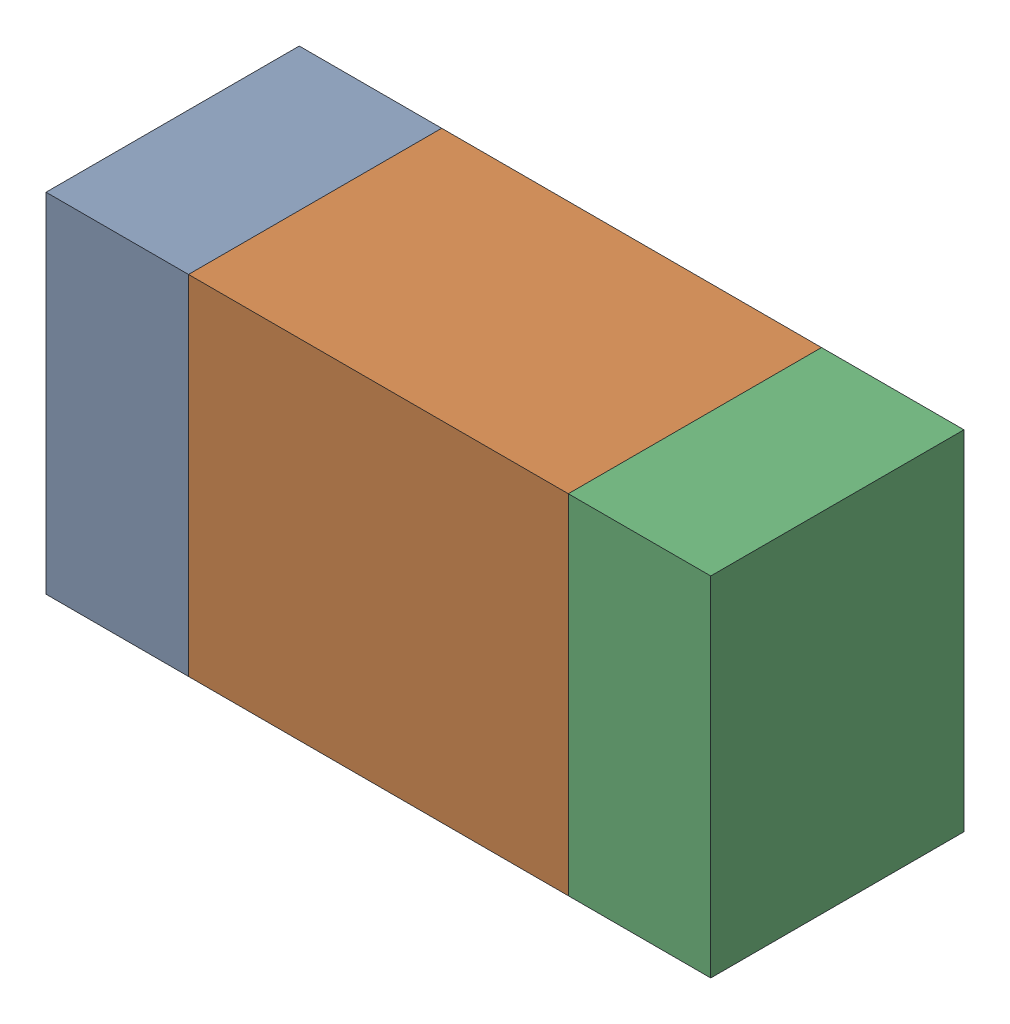
SolidWorks assembly R205PCB, configuration Default. Lengths in mm.
Overall size (1.05 0.55 0.4).
6 component instances, 2 part files, 0 mates.
Components (placement in the parent):
- 854785432-1: 854785432 [Default] at (94.2876 123.4001 0) size (0.22 0.55 0.4)
  - Extruded-1: Extruded [Default] at origin size (0.22 0.55 0.4)
- 854785568-1: 854785568 [Default] at (94.7001 123.4001 0) size (0.6 0.55 0.4)
  - Extruded_2-1: Extruded_2 [Default] at origin size (0.6 0.55 0.4)
- 854785432-2: 854785432 [Default] at (95.1126 123.4001 0) size (0.22 0.55 0.4)
  - Extruded-1: Extruded [Default] at origin size (0.22 0.55 0.4)
